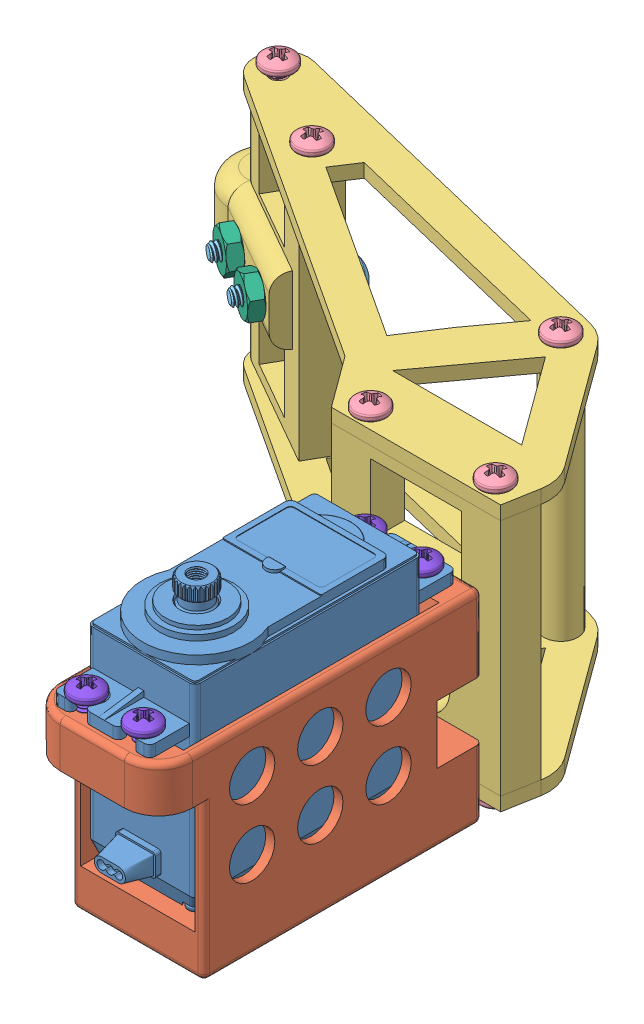
SolidWorks assembly XIAOTUI, configuration 默认. Lengths in mm.
Overall size (97.3 66.22 130.49).
22 component instances, 8 part files, 57 mates.
Components (placement in the parent):
- 复件 Servo MG996R^XIAOTUI-1: 复件 Servo MG996R^XIAOTUI [默认] at origin size (19 43.25 54) (virtual)
- 复件 Servo Mount^XIAOTUI-1: 复件 Servo Mount^XIAOTUI [默认] at (-9.5 -0.7174 0.5752) size (23.3 35.7 57) (virtual)
- 复件 Tibia Assembly^XIAOTUI-1: 复件 Tibia Assembly^XIAOTUI [默认] at (-76.5 18.227 -80.4) x (0 1 0) z (1 0 0) size (46.8 55.22 97.3) (virtual)
- 复件 4-40 x 0.375^XIAOTUI-1: 复件 4-40 x 0.375^XIAOTUI [默认] at (-11 4.352 -31.4) x (0.984563 0 0.175033) z (0 -1 0) size (5.56 5.56 11.49) (virtual)
- 复件 4-40 x 0.375^XIAOTUI-2: 复件 4-40 x 0.375^XIAOTUI [默认] at (11 4.352 -31.4) x (0.175033 0 -0.984563) z (0 -1 0) size (5.56 5.56 11.49) (virtual)
- 复件 4-40 x 0.375^XIAOTUI-3: 复件 4-40 x 0.375^XIAOTUI [默认] at (-5.5 4.352 -59.4) x (0.984563 0 0.175033) z (0 -1 0) size (5.56 5.56 11.49) (virtual)
- 复件 4-40 x 0.375^XIAOTUI-4: 复件 4-40 x 0.375^XIAOTUI [默认] at (-56.5274 4.352 -66.6299) x (0.984563 0 0.175033) z (0 -1 0) size (5.56 5.56 11.49) (virtual)
- 复件 4-40 x 0.375^XIAOTUI-5: 复件 4-40 x 0.375^XIAOTUI [默认] at (-70.4193 4.352 -74.5681) x (0.984563 0 0.175033) z (0 -1 0) size (5.56 5.56 11.49) (virtual)
- 复件 4-40 x 0.375^XIAOTUI-6: 复件 4-40 x 0.375^XIAOTUI [默认] at (11 32.102 -31.4) x (0.984563 0 0.175033) z (0 1 0) size (5.56 5.56 11.49) (virtual)
- 复件 4-40 x 0.375^XIAOTUI-7: 复件 4-40 x 0.375^XIAOTUI [默认] at (-5.5 32.102 -59.4) x (-0.175033 0 0.984563) z (0 1 0) size (5.56 5.56 11.49) (virtual)
- 复件 4-40 x 0.375^XIAOTUI-8: 复件 4-40 x 0.375^XIAOTUI [默认] at (-11 32.102 -31.4) x (-0.175033 0 0.984563) z (0 1 0) size (5.56 5.56 11.49) (virtual)
- 复件 4-40 x 0.375^XIAOTUI-9: 复件 4-40 x 0.375^XIAOTUI [默认] at (-56.5274 32.102 -66.6299) x (0.175033 0 -0.984563) z (0 1 0) size (5.56 5.56 11.49) (virtual)
- 复件 4-40 x 0.375^XIAOTUI-10: 复件 4-40 x 0.375^XIAOTUI [默认] at (-70.4193 33.3332 -74.5681) x (0.175033 0 -0.984563) z (0 1 0) size (5.56 5.56 11.49) (virtual)
- 复件 4-40 x 0.625^XIAOTUI-1: 复件 4-40 x 0.625^XIAOTUI [默认] at (-64.0302 18.227 -59.5467) x (-0.868078 0.019522 -0.496044) z (0.496139 0 -0.868243) size (5.56 5.56 17.84) (virtual)
- 复件 4-40 x 0.625^XIAOTUI-2: 复件 4-40 x 0.625^XIAOTUI [默认] at (-72.7105 18.227 -64.5118) x (-0.868078 0.019522 -0.496044) z (0.496139 0 -0.868243) size (5.56 5.56 17.84) (virtual)
- 复件 4-40 Nut^XIAOTUI-1: 复件 4-40 Nut^XIAOTUI [默认] at (-62.7002 18.227 -61.8731) x (-0.535914 -0.786894 -0.305933) z (-0.683382 0.617089 -0.390116) size (6.35 2.39 7.33) (virtual)
- 复件 4-40 Nut^XIAOTUI-2: 复件 4-40 Nut^XIAOTUI [默认] at (-71.3848 18.227 -66.8308) x (-0.197562 -0.973781 -0.11278) z (-0.845685 0.227486 -0.482769) size (6.35 2.39 7.33) (virtual)
- 复件 624Z Bearing^XIAOTUI-1: 复件 624Z Bearing^XIAOTUI [默认] at (-2.2057 -0.9 -3.5632) x (0.830401 0 0.557166) z (-0.557166 0 0.830401) size (13 5 13) (virtual)
- 复件 复件 (5) 4-40 x 0.375^XIAOTUI-1: 复件 复件 (5) 4-40 x 0.375^XIAOTUI [默认] at (-5 19.775 24.6) x (-1 0 0) z (0 1 0) size (5.56 5.56 11.49) (virtual)
- 复件 复件 (5) 4-40 x 0.375^XIAOTUI-2: 复件 复件 (5) 4-40 x 0.375^XIAOTUI [默认] at (-5 19.775 -24.4) x (0 0 1) z (0 1 0) size (5.56 5.56 11.49) (virtual)
- 复件 复件 (5) 4-40 x 0.375^XIAOTUI-3: 复件 复件 (5) 4-40 x 0.375^XIAOTUI [默认] at (5 19.775 24.6) x (1 0 0) z (0 1 0) size (5.56 5.56 11.49) (virtual)
- 复件 复件 (5) 4-40 x 0.375^XIAOTUI-4: 复件 复件 (5) 4-40 x 0.375^XIAOTUI [默认] at (5 19.775 -24.4) x (0 0 1) z (0 1 0) size (5.56 5.56 11.49) (virtual)
Mates (geometry in assembly coordinates):
- 重合4: coincident: plane of 复件 Servo MG996R^XIAOTUI-1 through (-4.25 27.3 23.5) normal (0 -1 0); plane of 复件 Servo Mount^XIAOTUI-1 through (0 27.3 22.6) normal (0 1 0)
- 同心1: concentric: cylinder of 复件 Servo MG996R^XIAOTUI-1 through (0 38.3 10.2) axis (0 1 0) radius 5.5; cylinder of 复件 Servo Mount^XIAOTUI-1 through (0 -8.4 10.2) axis (0 1 0) radius 6.5
- 平行2: parallel: plane of 复件 Servo MG996R^XIAOTUI-1 through (-9.5 3 -20) normal (-1 0 0); plane of 复件 Servo Mount^XIAOTUI-1 through (-10.05 12.95 0.1) normal (1 0 0)
- 重合7: coincident: plane of 复件 Servo Mount^XIAOTUI-1 through (0 14.102 -28.4) normal (0 0 -1); plane of 复件 Tibia Assembly^XIAOTUI-1 through (-14.9 18.227 -28.4) normal (0 0 1)
- 同心2: concentric: cylinder of 复件 Servo Mount^XIAOTUI-1 through (8 1 -28.4) axis (0 0 1) radius 1.13; cylinder of 复件 Tibia Assembly^XIAOTUI-1 through (8 1 -28.4) axis (0 0 -1) radius 1.5
- 同心3: concentric: cylinder of 复件 Servo Mount^XIAOTUI-1 through (8 17 -28.4) axis (0 0 1) radius 1.13; cylinder of 复件 Tibia Assembly^XIAOTUI-1 through (8 17 -28.4) axis (0 0 -1) radius 1.5
- 同心4: concentric: cylinder of 复件 Tibia Assembly^XIAOTUI-1 through (-11 -2.773 -31.4) axis (0 -1 0) radius 1.5; cylinder of 复件 4-40 x 0.375^XIAOTUI-1 through (-11 4.352 -31.4) axis (0 1 0) radius 2.7813
- 重合8: coincident: plane of 复件 Tibia Assembly^XIAOTUI-1 through (-30 -5.173 -54.4) normal (0 -1 0); plane of 复件 4-40 x 0.375^XIAOTUI-1 through (-11 -5.173 -31.4) normal (0 1 0)
- 平行3: parallel: plane of 复件 Tibia Assembly^XIAOTUI-1 through (14.9 18.227 -28.4) normal (0.984563 0 0.175033); plane of 复件 4-40 x 0.375^XIAOTUI-1 through (-11 4.352 -31.4) normal (0.984563 0 0.175033)
- 同心5: concentric: cylinder of 复件 Tibia Assembly^XIAOTUI-1 through (11 -2.773 -31.4) axis (0 -1 0) radius 1.5; cylinder of 复件 4-40 x 0.375^XIAOTUI-2 through (11 4.352 -31.4) axis (0 1 0) radius 2.7813
- 重合10: coincident: plane of 复件 Tibia Assembly^XIAOTUI-1 through (-30 -5.173 -54.4) normal (0 -1 0); plane of 复件 4-40 x 0.375^XIAOTUI-2 through (11 -5.173 -31.4) normal (0 1 0)
- 平行4: parallel: plane of 复件 Tibia Assembly^XIAOTUI-1 through (16.5 -2.773 -37.4) normal (0.984563 0 0.175033); plane of 复件 4-40 x 0.375^XIAOTUI-2 through (11 4.352 -31.4) normal (0.984563 0 0.175033)
- 同心6: concentric: cylinder of 复件 Tibia Assembly^XIAOTUI-1 through (-5.5 -2.773 -59.4) axis (0 -1 0) radius 1.5; cylinder of 复件 4-40 x 0.375^XIAOTUI-3 through (-5.5 4.352 -59.4) axis (0 1 0) radius 2.7813
- 重合12: coincident: plane of 复件 Tibia Assembly^XIAOTUI-1 through (-30 -5.173 -54.4) normal (0 -1 0); plane of 复件 4-40 x 0.375^XIAOTUI-3 through (-5.5 -5.173 -59.4) normal (0 1 0)
- 平行5: parallel: plane of 复件 Tibia Assembly^XIAOTUI-1 through (14.9 18.227 -28.4) normal (0.984563 0 0.175033); plane of 复件 4-40 x 0.375^XIAOTUI-3 through (-5.5 4.352 -59.4) normal (0.984563 0 0.175033)
- 同心7: concentric: cylinder of 复件 Tibia Assembly^XIAOTUI-1 through (-56.5274 -2.773 -66.6299) axis (0 -1 0) radius 1.5; cylinder of 复件 4-40 x 0.375^XIAOTUI-4 through (-56.5274 4.352 -66.6299) axis (0 1 0) radius 2.7813
- 重合14: coincident: plane of 复件 Tibia Assembly^XIAOTUI-1 through (-30 -5.173 -54.4) normal (0 -1 0); plane of 复件 4-40 x 0.375^XIAOTUI-4 through (-56.5274 -5.173 -66.6299) normal (0 1 0)
- 同心8: concentric: cylinder of 复件 Tibia Assembly^XIAOTUI-1 through (-70.4193 -2.773 -74.5681) axis (0 -1 0) radius 1.5; cylinder of 复件 4-40 x 0.375^XIAOTUI-5 through (-70.4193 4.352 -74.5681) axis (0 1 0) radius 2.7813
- 重合15: coincident: plane of 复件 Tibia Assembly^XIAOTUI-1 through (-30 -5.173 -54.4) normal (0 -1 0); plane of 复件 4-40 x 0.375^XIAOTUI-5 through (-70.4193 -5.173 -74.5681) normal (0 1 0)
- 平行6: parallel: plane of 复件 Tibia Assembly^XIAOTUI-1 through (14.9 18.227 -28.4) normal (0.984563 0 0.175033); plane of 复件 4-40 x 0.375^XIAOTUI-4 through (-56.5274 4.352 -66.6299) normal (0.984563 0 0.175033)
- 平行7: parallel: plane of 复件 Tibia Assembly^XIAOTUI-1 through (14.9 18.227 -28.4) normal (0.984563 0 0.175033); plane of 复件 4-40 x 0.375^XIAOTUI-5 through (-70.4193 4.352 -74.5681) normal (0.984563 0 0.175033)
- 同心9: concentric: cylinder of 复件 Tibia Assembly^XIAOTUI-1 through (11 39.227 -31.4) axis (0 1 0) radius 1.5; cylinder of 复件 4-40 x 0.375^XIAOTUI-6 through (11 32.102 -31.4) axis (0 -1 0) radius 2.7813
- 重合18: coincident: plane of 复件 Tibia Assembly^XIAOTUI-1 through (-30 41.627 -54.4) normal (0 1 0); plane of 复件 4-40 x 0.375^XIAOTUI-6 through (11 41.627 -31.4) normal (0 -1 0)
- 平行8: parallel: plane of 复件 Tibia Assembly^XIAOTUI-1 through (14.9 18.227 -28.4) normal (0.984563 0 0.175033); plane of 复件 4-40 x 0.375^XIAOTUI-6 through (11 32.102 -31.4) normal (0.984563 0 0.175033)
- 同心10: concentric: cylinder of 复件 Tibia Assembly^XIAOTUI-1 through (-11 39.227 -31.4) axis (0 1 0) radius 1.5; cylinder of 复件 4-40 x 0.375^XIAOTUI-8 through (-11 32.102 -31.4) axis (0 -1 0) radius 2.7813
- 重合20: coincident: plane of 复件 Tibia Assembly^XIAOTUI-1 through (-30 41.627 -54.4) normal (0 1 0); plane of 复件 4-40 x 0.375^XIAOTUI-8 through (-11 41.627 -31.4) normal (0 -1 0)
- 平行9: parallel: plane of 复件 Tibia Assembly^XIAOTUI-1 through (14.9 18.227 -28.4) normal (0.984563 0 0.175033); plane of 复件 4-40 x 0.375^XIAOTUI-8 through (-11 32.102 -31.4) normal (0.984563 0 0.175033)
- 同心11: concentric: cylinder of 复件 Tibia Assembly^XIAOTUI-1 through (-5.5 39.227 -59.4) axis (0 1 0) radius 1.5; cylinder of 复件 4-40 x 0.375^XIAOTUI-7 through (-5.5 32.102 -59.4) axis (0 -1 0) radius 2.7813
- 重合22: coincident: plane of 复件 Tibia Assembly^XIAOTUI-1 through (-30 41.627 -54.4) normal (0 1 0); plane of 复件 4-40 x 0.375^XIAOTUI-7 through (-5.5 41.627 -59.4) normal (0 -1 0)
- 平行10: parallel: plane of 复件 Tibia Assembly^XIAOTUI-1 through (14.9 18.227 -28.4) normal (0.984563 0 0.175033); plane of 复件 4-40 x 0.375^XIAOTUI-7 through (-5.5 32.102 -59.4) normal (0.984563 0 0.175033)
- 同心12: concentric: cylinder of 复件 Tibia Assembly^XIAOTUI-1 through (-56.5274 39.227 -66.6299) axis (0 1 0) radius 1.5; cylinder of 复件 4-40 x 0.375^XIAOTUI-9 through (-56.5274 32.102 -66.6299) axis (0 -1 0) radius 2.7813
- 重合24: coincident: plane of 复件 Tibia Assembly^XIAOTUI-1 through (-30 41.627 -54.4) normal (0 1 0); plane of 复件 4-40 x 0.375^XIAOTUI-9 through (-56.5274 41.627 -66.6299) normal (0 -1 0)
- 平行11: parallel: plane of 复件 Tibia Assembly^XIAOTUI-1 through (14.9 18.227 -28.4) normal (0.984563 0 0.175033); plane of 复件 4-40 x 0.375^XIAOTUI-9 through (-56.5274 32.102 -66.6299) normal (-0.984563 0 -0.175033)
- 同心13: concentric: cylinder of 复件 Tibia Assembly^XIAOTUI-1 through (-70.4193 39.227 -74.5681) axis (0 1 0) radius 1.5; cylinder of 复件 4-40 x 0.375^XIAOTUI-10 through (-70.4193 33.3332 -74.5681) axis (0 -1 0) radius 2.7813
- 平行12: parallel: plane of 复件 Tibia Assembly^XIAOTUI-1 through (14.9 18.227 -28.4) normal (0.984563 0 0.175033); plane of 复件 4-40 x 0.375^XIAOTUI-10 through (-70.4193 33.3332 -74.5681) normal (-0.984563 0 -0.175033)
- 同心14: concentric: cylinder of 复件 Tibia Assembly^XIAOTUI-1 through (-57.6437 18.227 -70.7231) axis (-0.496139 0 0.868243) radius 1.5; cylinder of 复件 4-40 x 0.625^XIAOTUI-1 through (-64.0302 18.227 -59.5467) axis (-0.496139 0 0.868243) radius 2.7813
- 相切1: tangent: circle of 复件 Tibia Assembly^XIAOTUI-1; plane of 复件 4-40 x 0.625^XIAOTUI-1 through (-56.1539 18.227 -73.3301) normal (-0.496139 0 0.868243)
- 同心15: concentric: cylinder of 复件 Tibia Assembly^XIAOTUI-1 through (-66.3261 18.227 -75.6845) axis (-0.496139 0 0.868243) radius 1.5; cylinder of 复件 4-40 x 0.625^XIAOTUI-2 through (-72.7105 18.227 -64.5118) axis (-0.496139 0 0.868243) radius 2.7813
- 相切2: tangent: circle of 复件 Tibia Assembly^XIAOTUI-1; plane of 复件 4-40 x 0.625^XIAOTUI-2 through (-64.8343 18.227 -78.2952) normal (-0.496139 0 0.868243)
- 同心16: concentric: circle of 复件 Tibia Assembly^XIAOTUI-1; circle of 复件 4-40 Nut^XIAOTUI-1
- 相切3: tangent: circle of 复件 Tibia Assembly^XIAOTUI-1; plane of 复件 4-40 Nut^XIAOTUI-1 through (-59.1557 19.5942 -61.2207) normal (0.495768 0 -0.868455)
- 同心17: concentric: circle of 复件 Tibia Assembly^XIAOTUI-1; circle of 复件 4-40 Nut^XIAOTUI-2
- 相切4: tangent: circle of 复件 Tibia Assembly^XIAOTUI-1; plane of 复件 4-40 Nut^XIAOTUI-2 through (-68.617 20.9018 -66.6218) normal (0.495768 0 -0.868455)
- 同心18: concentric: cylinder of 复件 Servo Mount^XIAOTUI-1 through (0 -8.4 10.2) axis (0 1 0) radius 6.5; cylinder of 复件 624Z Bearing^XIAOTUI-1 through (0 -5.9 10.2) axis (0 -1 0) radius 6.5
- 重合32: coincident: plane of 复件 Servo Mount^XIAOTUI-1 through (0 -3.4 10.2) normal (0 -1 0); plane of 复件 624Z Bearing^XIAOTUI-1 through (0 -3.4 10.2) normal (0 1 0)
- 同心19: concentric: cylinder of 复件 Servo Mount^XIAOTUI-1 through (-5 27.3 24.6) axis (0 -1 0) radius 1.13; cylinder of 复件 复件 (5) 4-40 x 0.375^XIAOTUI-1 through (-5 19.775 24.6) axis (0 -1 0) radius 2.7813
- 重合33: coincident: plane of 复件 Servo MG996R^XIAOTUI-1 through (-4.25 29.3 23.5) normal (0 1 0); plane of 复件 复件 (5) 4-40 x 0.375^XIAOTUI-1 through (-5 29.3 24.6) normal (0 -1 0)
- 平行14: parallel: plane of 复件 Servo Mount^XIAOTUI-1 through (-11.65 23.3 24.6) normal (-1 0 0); plane of 复件 复件 (5) 4-40 x 0.375^XIAOTUI-1 through (-5 19.775 24.6) normal (-1 0 0)
- 同心20: concentric: cylinder of 复件 Servo Mount^XIAOTUI-1 through (5 27.3 24.6) axis (0 -1 0) radius 1.13; cylinder of 复件 复件 (5) 4-40 x 0.375^XIAOTUI-3 through (5 19.775 24.6) axis (0 -1 0) radius 2.7813
- 重合35: coincident: plane of 复件 Servo MG996R^XIAOTUI-1 through (4.25 29.3 23.5) normal (0 1 0); plane of 复件 复件 (5) 4-40 x 0.375^XIAOTUI-3 through (5 29.3 24.6) normal (0 -1 0)
- 平行15: parallel: plane of 复件 Servo Mount^XIAOTUI-1 through (-11.65 23.3 24.6) normal (-1 0 0); plane of 复件 复件 (5) 4-40 x 0.375^XIAOTUI-3 through (5 19.775 24.6) normal (1 0 0)
- 同心21: concentric: cylinder of 复件 Servo Mount^XIAOTUI-1 through (5 27.3 -24.4) axis (0 -1 0) radius 1.13; cylinder of 复件 复件 (5) 4-40 x 0.375^XIAOTUI-4 through (5 19.775 -24.4) axis (0 -1 0) radius 2.7813
- 重合37: coincident: plane of 复件 Servo MG996R^XIAOTUI-1 through (4.25 29.3 -23.5) normal (0 1 0); plane of 复件 复件 (5) 4-40 x 0.375^XIAOTUI-4 through (5 29.3 -24.4) normal (0 -1 0)
- 平行16: parallel: plane of 复件 Servo Mount^XIAOTUI-1 through (-11.65 23.3 24.6) normal (-1 0 0); plane of 复件 复件 (5) 4-40 x 0.375^XIAOTUI-4 through (5 19.775 -24.4) normal (1 0 0)
- 同心22: concentric: cylinder of 复件 Servo Mount^XIAOTUI-1 through (-5 27.3 -24.4) axis (0 -1 0) radius 1.13; cylinder of 复件 复件 (5) 4-40 x 0.375^XIAOTUI-2 through (-5 19.775 -24.4) axis (0 -1 0) radius 2.7813
- 重合39: coincident: plane of 复件 Servo MG996R^XIAOTUI-1 through (-4.25 29.3 -23.5) normal (0 1 0); plane of 复件 复件 (5) 4-40 x 0.375^XIAOTUI-2 through (-5 29.3 -24.4) normal (0 -1 0)
- 平行17: parallel: plane of 复件 Servo Mount^XIAOTUI-1 through (-11.65 23.3 24.6) normal (-1 0 0); plane of 复件 复件 (5) 4-40 x 0.375^XIAOTUI-2 through (-5 19.775 -24.4) normal (1 0 0)
